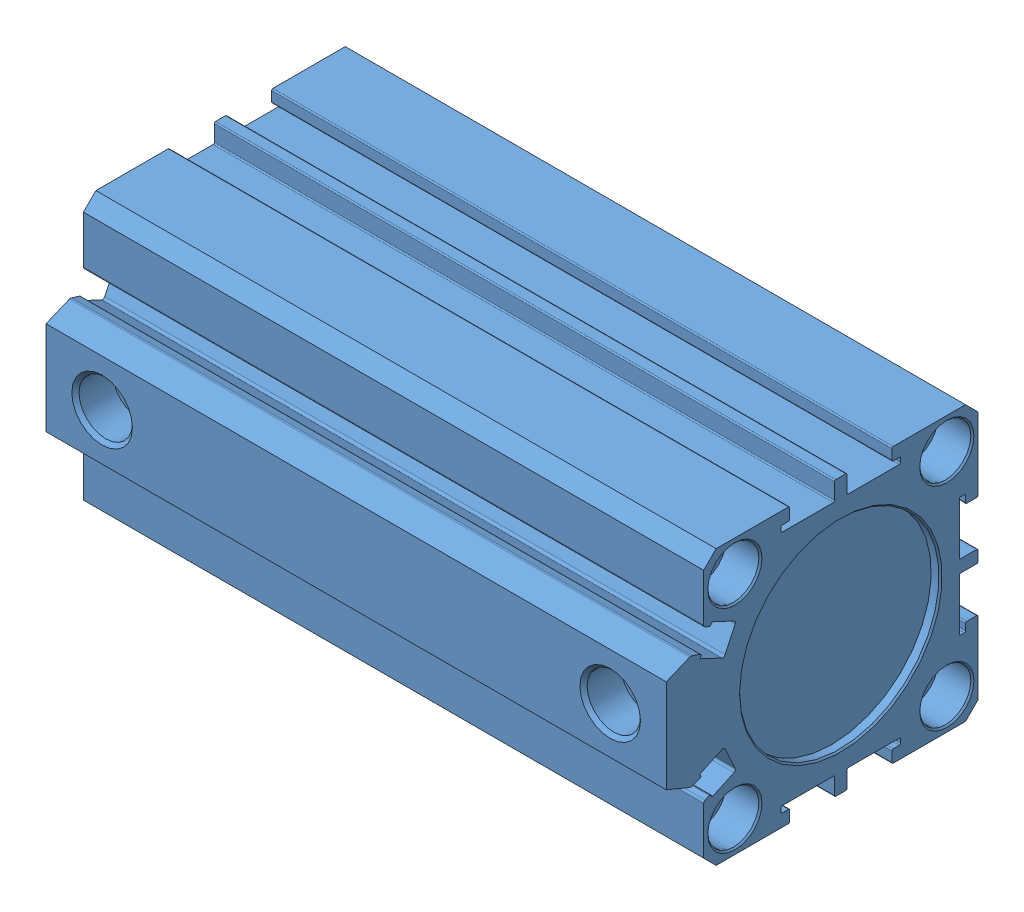
SolidWorks assembly SDA32x75, configuration Default. Lengths in mm.
Overall size (106.5 44 50).
2 component instances, 2 part files, 3 mates.
Components (placement in the parent):
- _SDA-32x7575_b-1: _SDA-32x7575_b [Default] x (1 0 0) z (0 -1 0) size (102.5 50 44)
- _SDA-32x7575_r-1: _SDA-32x7575_r [Default] at origin size (100.5 31.9 31.9)
Mates (geometry in assembly coordinates):
- LimitDistance1: limit distance = 4 mm aligned: plane of _SDA-32x7575_r-1 through (-7 0 0) normal (-1 0 0); plane of _SDA-32x7575_b-1 through (-3 0 10) normal (-1 0 0)
- Concentric1: concentric aligned: cylinder of _SDA-32x7575_b-1 through (93.5 0 0) axis (-1 0 0) radius 6; cylinder of _SDA-32x7575_r-1 through (0 0 0) axis (-1 0 0) radius 6
- Parallel1: parallel aligned: plane of _SDA-32x7575_b-1 through (99.5 7.5 28) normal (0 0 1); plane of _SDA-32x7575_r-1 through (-4 10 5) normal (0 0 1)
